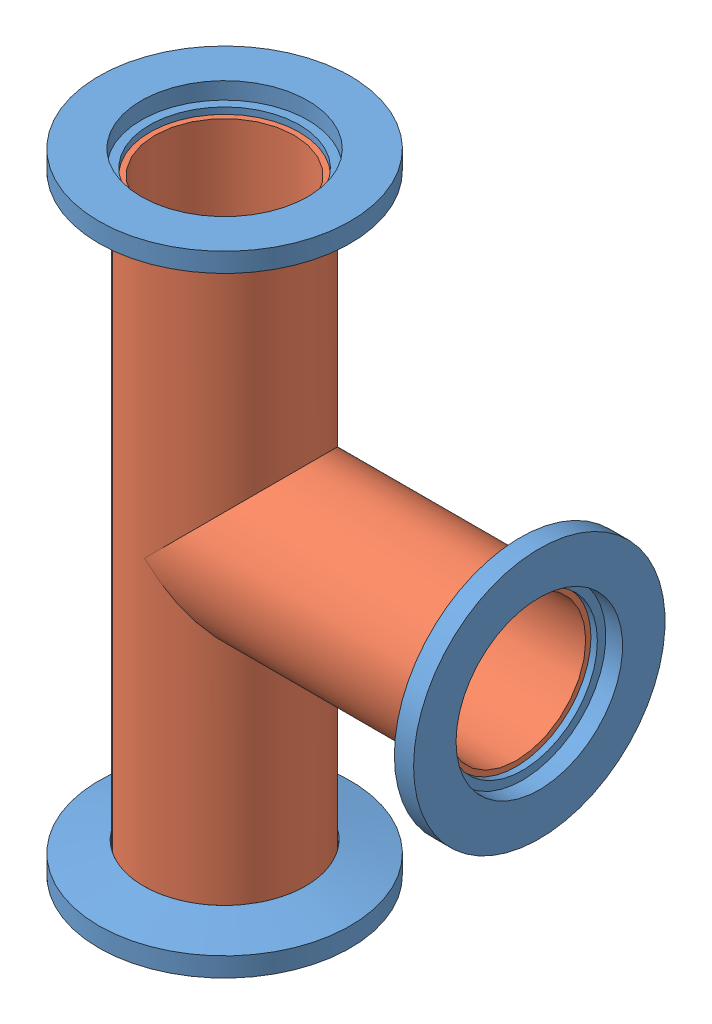
SolidWorks assembly qf25-100-t, configuration Default. Lengths in mm.
Overall size (69.85 99.82 39.88).
4 component instances, 2 part files, 0 mates.
Components (placement in the parent):
- P0001498-1: P0001498 [Default] at (0 47.4345 0) x (0 0 -1) z (0 -1 0) size (39.88 39.88 4.95)
- P0001498-2: P0001498 [Default] at (47.4345 0 0) x (0 0 -1) z (-1 0 0) size (39.88 39.88 4.95)
- P0001498-3: P0001498 [Default] at (0 -47.4345 0) x (0 0 -1) z (0 1 0) size (39.88 39.88 4.95)
- P0017967-1: P0017967 [Default] at origin size (58.93 92.46 25.4)
